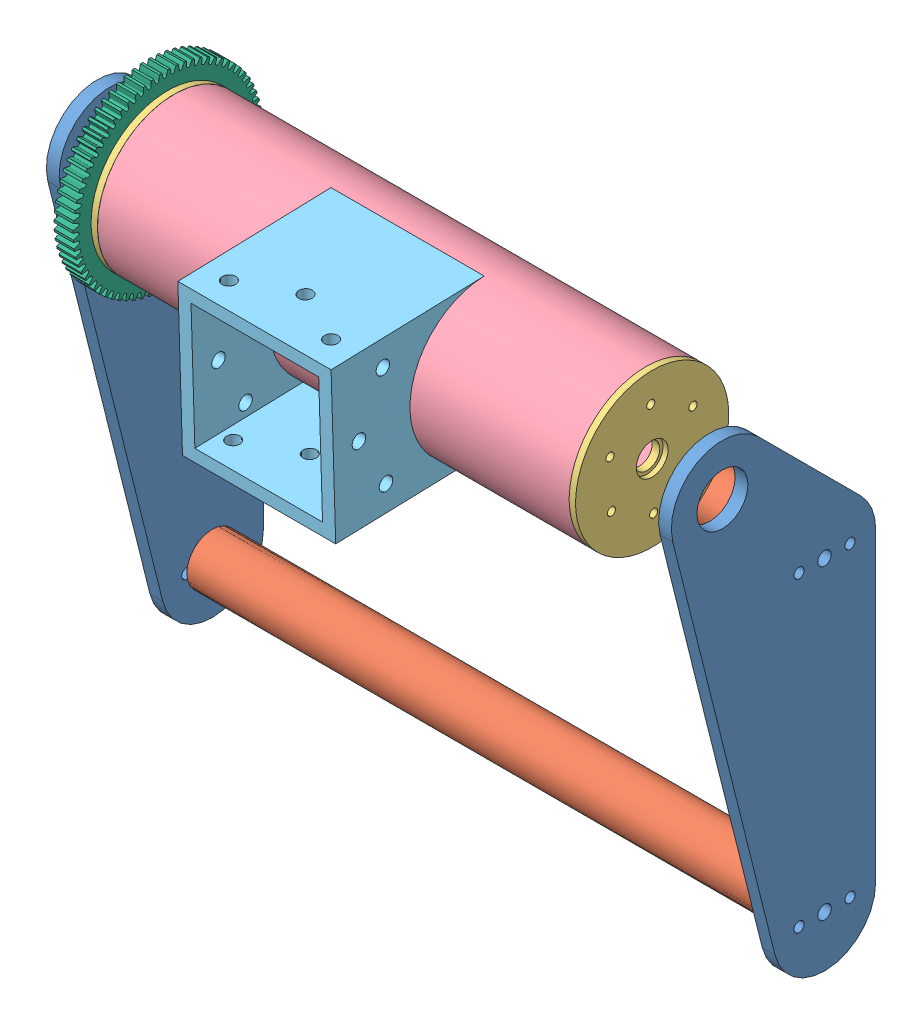
SolidWorks assembly 2018-304-A(copy), configuration Default. Lengths in mm.
Overall size (310.85 277.44 153.8).
12 component instances, 6 part files, 1 mates.
Components (placement in the parent):
- 2018-306-A-1: 2018-306-A [Default] at origin size (310.85 277.44 153.8)
  - 2018-305-A-1: 2018-305-A [Default] at origin size (310.85 254 101.6)
    - 2018-305-D001-1: 2018-305-D001 [Default] at (177.8 0 0) size (6.35 254 101.6)
    - 2018-305-D002-2: 2018-305-D002 [Default] at (28.7274 -50.8 -50.8) x (0 -0.477133 -0.878831) z (1 0 0) size (25.4 25.4 298.15)
    - 2018-305-D002-3: 2018-305-D002 [Default] at (28.7274 -203.2 -50.8) x (0 -0.477133 -0.878831) z (1 0 0) size (25.4 25.4 298.15)
    - 2018-305-D001-2: 2018-305-D001 [Default] at (-126.6952 0 0) size (6.35 254 101.6)
  - 2018-303-A-1: 2018-303-A [Default] at (-100.9524 -39.6903 -66.8984) x (1 0 0) z (0 -0.030169 0.999545) size (252.08 94.86 123.63)
    - 2018-303-D005-1: 2018-303-D005 [Default] at (9.1822 41.6905 65.6706) size (6.35 76.2 76.2)
    - 2018-303-D002-1: 2018-303-D002 [Default] at (129.6798 41.6905 65.6706) x (1 0 0) z (0 0.972075 -0.234672) size (234.65 76.2 76.2)
    - 2018-303-D005-2: 2018-303-D005 [Default] at (250.1774 41.6905 65.6706) x (-1 0 0) z (0 0 -1) size (6.35 76.2 76.2)
    - 2018-303-D004-1: 2018-303-D004 [Default] at (91.5798 3.5905 65.6706) size (76.2 76.2 76.2)
    - 72t_Aluminum_Spur_Gear_20_DP_1_2_Hex_Bore_VersaKeys_217-2716-1: 72t_Aluminum_Spur_Gear_20_DP_1_2_Hex_Bore_VersaKeys_217-2716 [Default] at (4.4197 41.6905 65.6706) x (0 0 1) z (-1 0 0) size (94.86 94.86 12.65)
Mates (geometry in assembly coordinates):
- Coincident1: coordinate: point of ?
